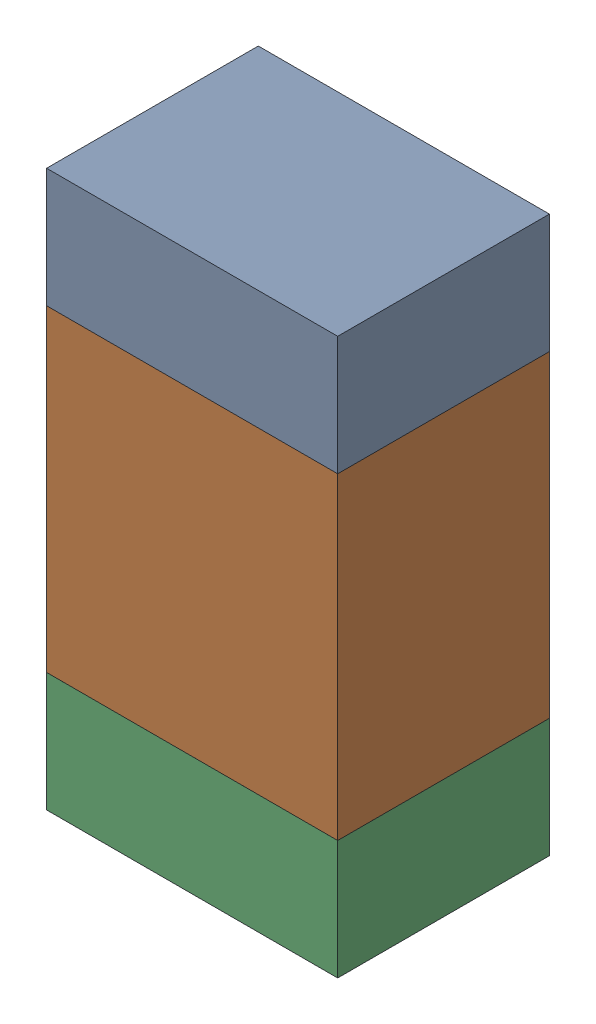
SolidWorks assembly R100_1PCB, configuration Default. Lengths in mm.
Overall size (0.55 1.05 0.4).
6 component instances, 2 part files, 0 mates.
Components (placement in the parent):
- 846483288-1: 846483288 [Default] at (117.1001 121.4124 0) size (0.55 0.22 0.4)
  - Extruded_12-1: Extruded_12 [Default] at origin size (0.55 0.22 0.4)
- 846483424-1: 846483424 [Default] at (117.1001 120.9999 0) size (0.55 0.6 0.4)
  - Extruded_13-1: Extruded_13 [Default] at origin size (0.55 0.6 0.4)
- 846483288-2: 846483288 [Default] at (117.1001 120.5874 0) size (0.55 0.22 0.4)
  - Extruded_12-1: Extruded_12 [Default] at origin size (0.55 0.22 0.4)
